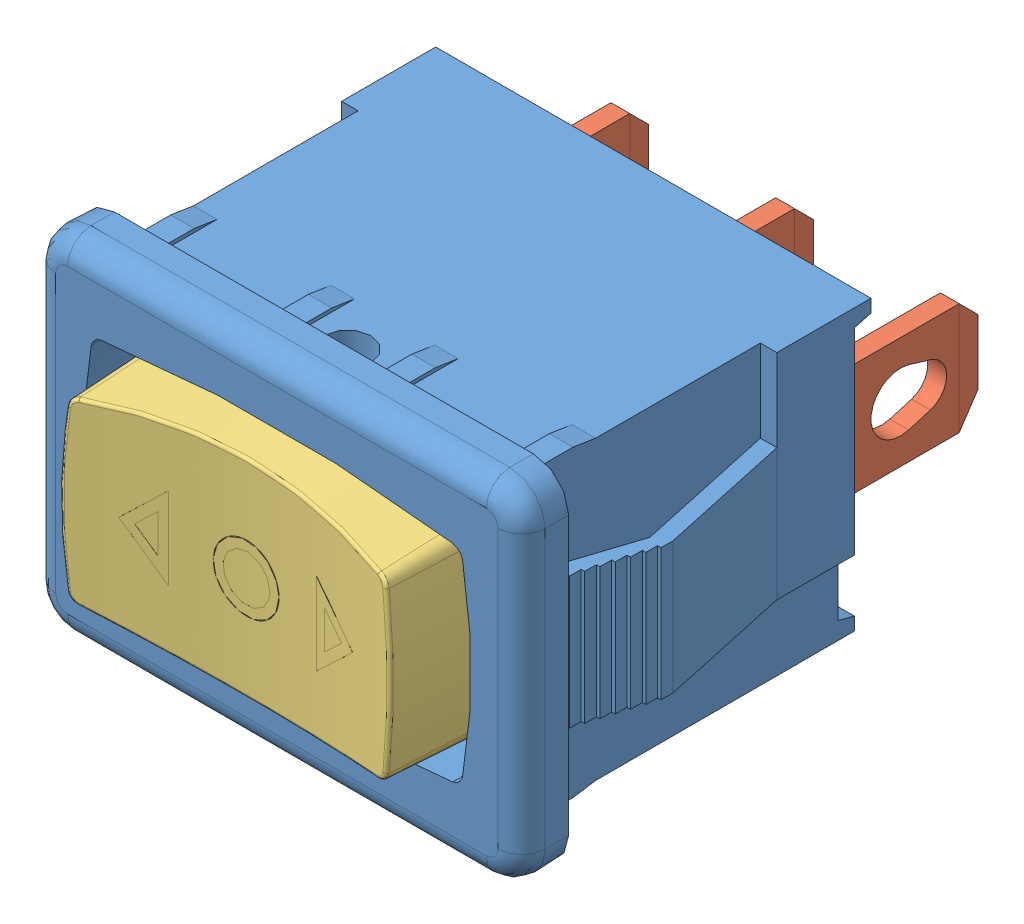
SolidWorks assembly panelMountSwitch, configuration Default. Lengths in mm.
Overall size (20.94 14.8 24.82).
9 component instances, 6 part files, 6 mates.
Components (placement in the parent):
- R1966IBLKBLKHF-1: R1966IBLKBLKHF [Default] at (0 0 -14) size (20.94 14.8 24.82)
  - Copy of R1966 HOUSING STD^R1966IBLKBLKHF-1: Copy of R1966 HOUSING STD^R1966IBLKBLKHF [Default] at origin size (20.94 14.8 16) (virtual)
  - Copy of R1966 TERM F^R1966IBLKBLKHF-1: Copy of R1966 TERM F^R1966IBLKBLKHF [Default] at (-7 0 0.7) size (0.8 6.88 8.3) (virtual)
  - Copy of R1966 TERM F^R1966IBLKBLKHF-2: Copy of R1966 TERM F^R1966IBLKBLKHF [Default] at (0 0 0.7) size (0.8 6.88 8.3) (virtual)
  - Copy of R1966 TERM F^R1966IBLKBLKHF-3: Copy of R1966 TERM F^R1966IBLKBLKHF [Default] at (7 0 0.7) size (0.8 6.88 8.3) (virtual)
  - Copy of ACUATOR H^R1966IBLKBLKHF-1: Copy of ACUATOR H^R1966IBLKBLKHF [Default] at (0 0 11.47) x (-1 0 0) z (0 0 1) size (14.75 11.6 8.75) (virtual)
- guaranteedEmbedmentTool^panelMountSwitch-1: guaranteedEmbedmentTool^panelMountSwitch [Default] at origin size (24.2 13.4 2.2) (hidden, virtual)
- panelAddition^panelMountSwitch-1: panelAddition^panelMountSwitch [Default] at origin size (24.2 13.4 2.2) (hidden, virtual)
- panelSubtraction^panelMountSwitch-1: panelSubtraction^panelMountSwitch [Default] at origin size (24.2 13.4 3.3) (hidden, virtual)
Mates (geometry in assembly coordinates):
- Coincident10: coordinate: point of ?
- Coincident11: coordinate: unknown of ?
- Coincident12: coordinate: unknown of ?
- Coincident13: coincident: unknown of R1966IBLKBLKHF-1/Copy of R1966 HOUSING STD^R1966IBLKBLKHF-1
- Coincident14: coincident anti-aligned: plane of R1966IBLKBLKHF-1/Copy of R1966 HOUSING STD^R1966IBLKBLKHF-1 through (0 0 0) normal (0 0 -1); plane of assembly through (0 0 0) normal (0 0 1)
- Parallel1: parallel aligned: line of R1966IBLKBLKHF-1/Copy of R1966 HOUSING STD^R1966IBLKBLKHF-1 through (-11.519 0 -14) axis (1 0 0)
